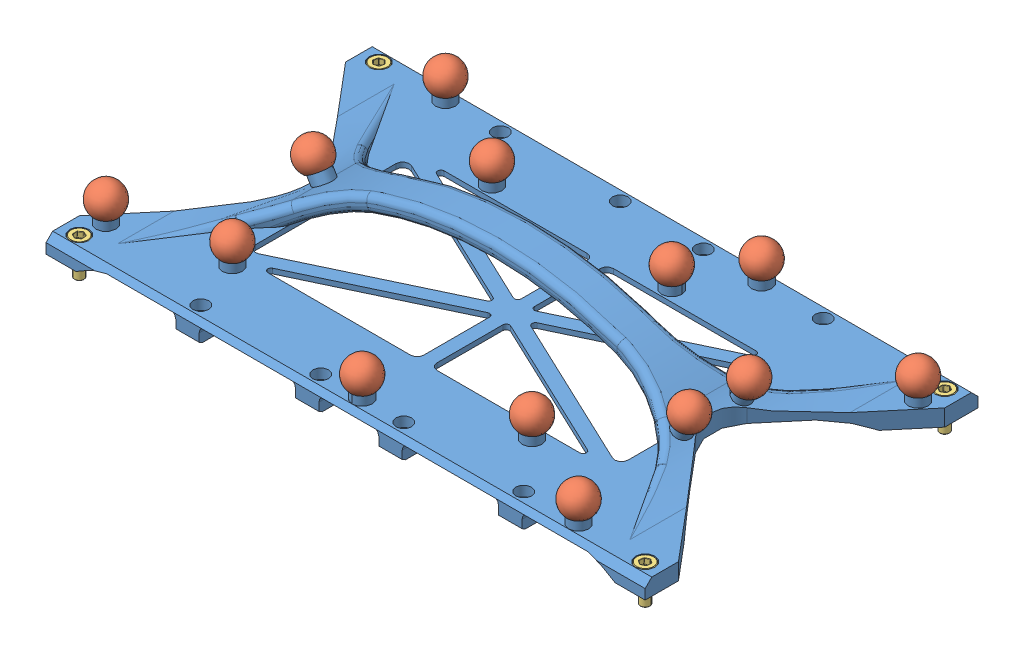
SolidWorks assembly body_structure_center_vicon, configuration Standard. Lengths in mm.
Overall size (180.57 32.26 103.3).
18 component instances, 3 part files, 36 mates.
Components (placement in the parent):
- body_structure_center_vicon-1: body_structure_center_vicon [Standard] at origin size (180 27.76 100)
- vicon_marker_10mm-1: vicon_marker_10mm [Standard] at (-65 11.35 -45) x (0.558453 0 -0.829536) z (0.829536 0 0.558453) size (9.7 13.2 9.7)
- vicon_marker_10mm-2: vicon_marker_10mm [Standard] at (-84 11.35 38) x (-0.47422 0 -0.880406) z (0.880406 0 -0.47422) size (9.7 13.2 9.7)
- vicon_marker_10mm-3: vicon_marker_10mm [Standard] at (84 11.35 -38) x (-0.08783 0 -0.996135) z (0.996135 0 -0.08783) size (9.7 13.2 9.7)
- vicon_marker_10mm-4: vicon_marker_10mm [Standard] at (65 11.35 45) x (-0.972254 0 -0.233926) z (0.233926 0 -0.972254) size (9.7 13.2 9.7)
- vicon_marker_10mm-5: vicon_marker_10mm [Standard] at (-59.7097 16.1191 0) x (0.489829 0.292885 -0.82115) z (0.704772 0.421406 0.570713) size (9.7 13.2 9.7)
- vicon_marker_10mm-6: vicon_marker_10mm [Standard] at (62.2632 14.5898 9) x (0.533773 -0.201989 -0.82115) z (0.768 -0.290625 0.570713) size (9.7 13.2 9.7)
- vicon_marker_10mm-7: vicon_marker_10mm [Standard] at (62.2632 14.5898 -9) x (0.533773 -0.201989 -0.82115) z (0.768 -0.290625 0.570713) size (9.7 13.2 9.7)
- vicon_marker_10mm-8: vicon_marker_10mm [Standard] at (-54 11.35 30) x (-0.47422 0 -0.880406) z (0.880406 0 -0.47422) size (9.7 13.2 9.7)
- vicon_marker_10mm-9: vicon_marker_10mm [Standard] at (0 11.35 45) x (-0.47422 0 -0.880406) z (0.880406 0 -0.47422) size (9.7 13.2 9.7)
- vicon_marker_10mm-11: vicon_marker_10mm [Standard] at (36 11.35 30) x (-0.47422 0 -0.880406) z (0.880406 0 -0.47422) size (9.7 13.2 9.7)
- vicon_marker_10mm-12: vicon_marker_10mm [Standard] at (-36 11.35 -30) x (-0.855175 0 -0.518339) z (0.518339 0 -0.855175) size (9.7 13.2 9.7)
- vicon_marker_10mm-13: vicon_marker_10mm [Standard] at (18 11.35 -30) x (-0.846823 0 -0.531875) z (0.531875 0 -0.846823) size (9.7 13.2 9.7)
- vicon_marker_10mm-14: vicon_marker_10mm [Standard] at (30 11.35 -45) x (-0.47422 0 -0.880406) z (0.880406 0 -0.47422) size (9.7 13.2 9.7)
- fastener_shcs_m3_8-1: fastener_shcs_m3_8 [Standard] at (85 2 -45) x (-0.450175 0 -0.89294) z (0 1 0) size (5.5 5.5 11)
- fastener_shcs_m3_8-2: fastener_shcs_m3_8 [Standard] at (85 2 45) x (-0.404015 0 -0.914752) z (0 1 0) size (5.5 5.5 11)
- fastener_shcs_m3_8-3: fastener_shcs_m3_8 [Standard] at (-85 2 -45) x (0.272102 0 0.962268) z (0 1 0) size (5.5 5.5 11)
- fastener_shcs_m3_8-4: fastener_shcs_m3_8 [Standard] at (-85 2 45) x (-0.558477 0 -0.82952) z (0 1 0) size (5.5 5.5 11)
Mates (geometry in assembly coordinates):
- Konzentrisch1: concentric aligned: cylinder of body_structure_center_vicon-1 through (-65 -1.5 -45) axis (0 1 0) radius 1.4; cylinder of vicon_marker_10mm-1 through (-65 3 -45) axis (0 1 0) radius 2
- Deckungsgleich1: coincident anti-aligned: plane of body_structure_center_vicon-1 through (-65 8 -45) normal (0 1 0); plane of vicon_marker_10mm-1 through (-65 8 -45) normal (0 -1 0)
- Konzentrisch2: concentric aligned: cylinder of body_structure_center_vicon-1 through (-84 -1.5 38) axis (0 1 0) radius 1.4; cylinder of vicon_marker_10mm-2 through (-84 3 38) axis (0 1 0) radius 2
- Deckungsgleich2: coincident anti-aligned: plane of body_structure_center_vicon-1 through (-84 8 38) normal (0 1 0); plane of vicon_marker_10mm-2 through (-84 8 38) normal (0 -1 0)
- Konzentrisch3: concentric aligned: cylinder of body_structure_center_vicon-1 through (84 -1.5 -38) axis (0 1 0) radius 1.4; cylinder of vicon_marker_10mm-3 through (84 3 -38) axis (0 1 0) radius 2
- Deckungsgleich3: coincident anti-aligned: plane of body_structure_center_vicon-1 through (84 8 -38) normal (0 1 0); plane of vicon_marker_10mm-3 through (84 8 -38) normal (0 -1 0)
- Konzentrisch4: concentric aligned: cylinder of body_structure_center_vicon-1 through (65 -1.5 45) axis (0 1 0) radius 1.4; cylinder of vicon_marker_10mm-4 through (65 3 45) axis (0 1 0) radius 2
- Deckungsgleich4: coincident anti-aligned: plane of body_structure_center_vicon-1 through (65 8 45) normal (0 1 0); plane of vicon_marker_10mm-4 through (65 8 45) normal (0 -1 0)
- Konzentrisch5: concentric anti-aligned: cylinder of body_structure_center_vicon-1 through (69.6002 33.9784 -9) axis (-0.353925 -0.935274 0) radius 1.4; cylinder of vicon_marker_10mm-7 through (59.3079 6.7803 -9) axis (0.353925 0.935274 0) radius 2
- Deckungsgleich5: coincident anti-aligned: plane of body_structure_center_vicon-1 through (61.0776 11.4566 -9) normal (0.353925 0.935274 0); plane of vicon_marker_10mm-7 through (61.0776 11.4566 -9) normal (-0.353925 -0.935274 0)
- Konzentrisch6: concentric anti-aligned: cylinder of body_structure_center_vicon-1 through (69.6002 33.9784 9) axis (-0.353925 -0.935274 0) radius 1.4; cylinder of vicon_marker_10mm-6 through (59.3079 6.7803 9) axis (0.353925 0.935274 0) radius 2
- Deckungsgleich6: coincident anti-aligned: plane of body_structure_center_vicon-1 through (61.0776 11.4566 9) normal (0.353925 0.935274 0); plane of vicon_marker_10mm-6 through (61.0776 11.4566 9) normal (-0.353925 -0.935274 0)
- Konzentrisch7: concentric anti-aligned: cylinder of body_structure_center_vicon-1 through (-72.1533 36.93 0) axis (0.513191 -0.858275 0) radius 1.4; cylinder of vicon_marker_10mm-5 through (-55.4246 8.9525 0) axis (-0.513191 0.858275 0) radius 2
- Deckungsgleich7: coincident anti-aligned: plane of body_structure_center_vicon-1 through (-57.9905 13.2438 0) normal (-0.513191 0.858275 0); plane of vicon_marker_10mm-5 through (-57.9905 13.2438 0) normal (0.513191 -0.858275 0)
- Konzentrisch8: concentric aligned: cylinder of body_structure_center_vicon-1 through (-54 -1.5 30) axis (0 1 0) radius 1.4; cylinder of vicon_marker_10mm-8 through (-54 3 30) axis (0 1 0) radius 2
- Deckungsgleich8: coincident anti-aligned: plane of body_structure_center_vicon-1 through (-54 8 30) normal (0 1 0); plane of vicon_marker_10mm-8 through (-54 8 30) normal (0 -1 0)
- Konzentrisch9: concentric: cylinder of body_structure_center_vicon-1 through (-30 -1.5 45) axis (0 1 0) radius 1.65; cylinder of ? through (-30 3 45) axis (0 1 0) radius 2
- Deckungsgleich9: coincident: plane of body_structure_center_vicon-1 through (-30 8 45) normal (0 1 0); plane of ? through (-30 8 45) normal (0 -1 0)
- Konzentrisch10: concentric aligned: cylinder of body_structure_center_vicon-1 through (0 -1.5 45) axis (0 1 0) radius 1.4; cylinder of vicon_marker_10mm-9 through (0 3 45) axis (0 1 0) radius 2
- Deckungsgleich10: coincident anti-aligned: plane of body_structure_center_vicon-1 through (0 8 45) normal (0 1 0); plane of vicon_marker_10mm-9 through (0 8 45) normal (0 -1 0)
- Konzentrisch11: concentric aligned: cylinder of body_structure_center_vicon-1 through (36 -1.5 30) axis (0 1 0) radius 1.4; cylinder of vicon_marker_10mm-11 through (36 3 30) axis (0 1 0) radius 2
- Deckungsgleich11: coincident anti-aligned: plane of body_structure_center_vicon-1 through (36 8 30) normal (0 1 0); plane of vicon_marker_10mm-11 through (36 8 30) normal (0 -1 0)
- Konzentrisch12: concentric aligned: cylinder of vicon_marker_10mm-12 through (-36 3 -30) axis (0 1 0) radius 2; cylinder of body_structure_center_vicon-1 through (-36 -1.5 -30) axis (0 1 0) radius 1.4
- Deckungsgleich12: coincident anti-aligned: plane of body_structure_center_vicon-1 through (-36 8 -30) normal (0 1 0); plane of vicon_marker_10mm-12 through (-36 8 -30) normal (0 -1 0)
- Konzentrisch14: concentric aligned: cylinder of body_structure_center_vicon-1 through (30 -1.5 -45) axis (0 1 0) radius 1.4; cylinder of vicon_marker_10mm-14 through (30 3 -45) axis (0 1 0) radius 2
- Deckungsgleich13: coincident anti-aligned: plane of body_structure_center_vicon-1 through (30 8 -45) normal (0 1 0); plane of vicon_marker_10mm-14 through (30 8 -45) normal (0 -1 0)
- Konzentrisch15: concentric aligned: cylinder of body_structure_center_vicon-1 through (18 -1.5 -30) axis (0 1 0) radius 1.4; cylinder of vicon_marker_10mm-13 through (18 3 -30) axis (0 1 0) radius 2
- Deckungsgleich15: coincident anti-aligned: plane of body_structure_center_vicon-1 through (18 8 -30) normal (0 1 0); plane of vicon_marker_10mm-13 through (18 8 -30) normal (0 -1 0)
- Konzentrisch16: concentric anti-aligned: cylinder of body_structure_center_vicon-1 through (85 26.2588 -45) axis (0 -1 0) radius 1.5; cylinder of fastener_shcs_m3_8-1 through (85 23.9199 -45) axis (0 1 0) radius 1.465
- Konzentrisch17: concentric anti-aligned: cylinder of body_structure_center_vicon-1 through (85 26.2588 45) axis (0 -1 0) radius 1.5; cylinder of fastener_shcs_m3_8-2 through (85 23.9199 45) axis (0 1 0) radius 1.465
- Konzentrisch18: concentric anti-aligned: cylinder of body_structure_center_vicon-1 through (-85 26.2588 45) axis (0 -1 0) radius 1.5; cylinder of fastener_shcs_m3_8-4 through (-85 23.9199 45) axis (0 1 0) radius 1.465
- Konzentrisch19: concentric anti-aligned: cylinder of body_structure_center_vicon-1 through (-85 26.2588 -45) axis (0 -1 0) radius 1.5; cylinder of fastener_shcs_m3_8-3 through (-85 23.9199 -45) axis (0 1 0) radius 1.465
- Deckungsgleich16: coincident anti-aligned: plane of body_structure_center_vicon-1 through (-85 2 45) normal (0 1 0); plane of fastener_shcs_m3_8-4 through (-87.2812 2 46.5358) normal (0 -1 0)
- Deckungsgleich17: coincident anti-aligned: plane of body_structure_center_vicon-1 through (-85 2 -45) normal (0 1 0); plane of fastener_shcs_m3_8-3 through (-82.3538 2 -45.7483) normal (0 -1 0)
- Deckungsgleich18: coincident anti-aligned: plane of body_structure_center_vicon-1 through (85 2 -45) normal (0 1 0); plane of fastener_shcs_m3_8-1 through (82.5444 2 -43.762) normal (0 -1 0)
- Deckungsgleich19: coincident anti-aligned: plane of body_structure_center_vicon-1 through (85 2 45) normal (0 1 0); plane of fastener_shcs_m3_8-2 through (82.4844 2 46.111) normal (0 -1 0)
